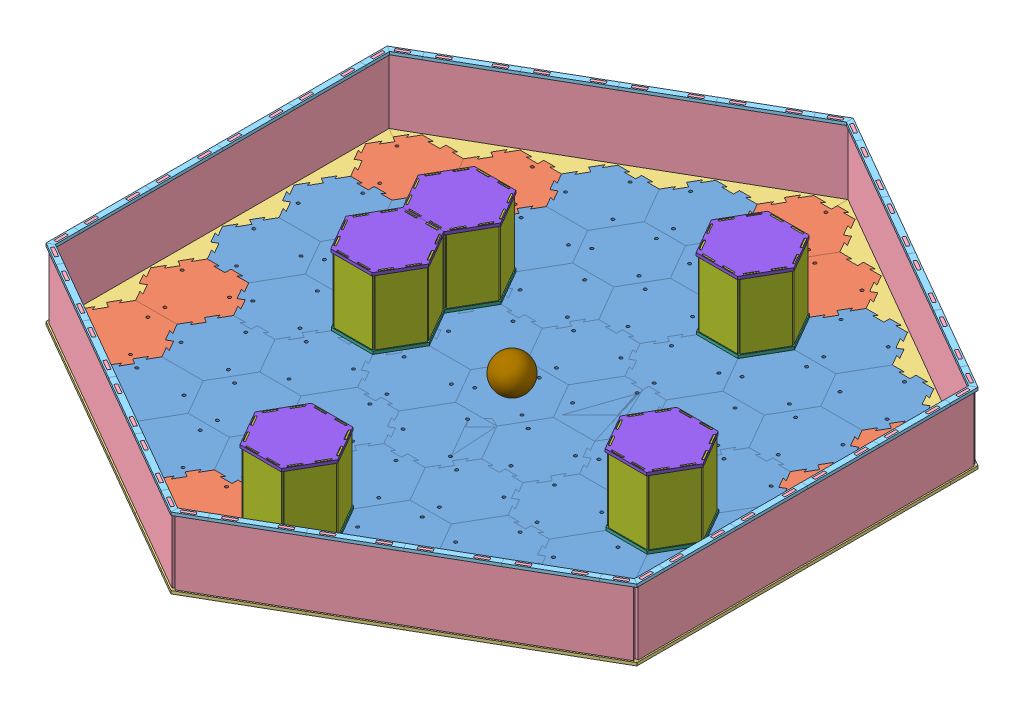
SolidWorks assembly examplepuzzle, configuration Default. Lengths in mm.
Overall size (1619.25 158.75 1704.77).
84 component instances, 9 part files, 90 mates.
Components (placement in the parent):
- module-1: module [Default] at origin size (444.5 6.35 474.64)
- module-2: module [Default] at (-400.05 0 -76.9897) size (444.5 6.35 474.64)
- module-3: module [Default] at (-266.7 0 307.9586) x (0.5 0 -0.866025) z (0.866025 0 0.5) size (444.5 6.35 474.64)
- module-5: module [Default] at (133.35 0 384.9483) x (-0.5 0 -0.866025) z (0.866025 0 -0.5) size (444.5 6.35 474.64)
- module-7: module [Default] at (400.05 0 76.9897) x (-1 0 0) z (0 0 -1) size (444.5 6.35 474.64)
- module-11: module [Default] at (266.7 0 -307.9586) size (444.5 6.35 474.64)
- module-12: module [Default] at (-133.35 0 -384.9483) size (444.5 6.35 474.64)
- module-13: module [Default] at origin size (444.5 6.35 474.64)
- module_2cell-1: module_2cell [Default] at (-133.35 0 538.9276) size (311.15 6.35 243.67)
- module_2cell-2: module_2cell [Default] at (400.05 0 384.9483) x (0.5 0 -0.866025) z (0.866025 0 0.5) size (311.15 6.35 243.67)
- module_2cell-4: module_2cell [Default] at (133.35 0 -538.9276) x (-1 0 0) z (0 0 -1) size (311.15 6.35 243.67)
- module_2cell-6: module_2cell [Default] at (-400.05 0 -384.9483) x (-0.5 0 0.866025) z (-0.866025 0 -0.5) size (311.15 6.35 243.67)
- module_2cell-9: module_2cell [Default] at (-533.4 0 153.9793) x (0.5 0 0.866025) z (-0.866025 0 0.5) size (311.15 6.35 243.67)
- module_2cell-11: module_2cell [Default] at (533.4 0 -153.9793) x (-0.5 0 -0.866025) z (0.866025 0 -0.5) size (311.15 6.35 243.67)
- Wall_seg_assembly-1: Wall_seg_assembly [Default] at (622.3 0 -230.969) x (0 0 1) z (-1 0 0) size (733.23 152.4 88.9)
  - border-1: border [Default] at origin size (733.23 6.35 88.9)
  - Wall_seg-1: Wall_seg [Default] at (230.969 69.85 -9.525) x (1 0 0) z (0 -1 0) size (721.64 6.35 152.4)
- Wall_seg_assembly-2: Wall_seg_assembly [Default] at (111.125 0 -654.4121) x (0.866025 0 0.5) z (-0.5 0 0.866025) size (733.23 152.4 88.9)
  - border-1: border [Default] at origin size (733.23 6.35 88.9)
  - Wall_seg-1: Wall_seg [Default] at (230.969 69.85 -9.525) x (1 0 0) z (0 -1 0) size (721.64 6.35 152.4)
- Wall_seg_assembly-4: Wall_seg_assembly [Default] at (-511.175 0 -423.4431) x (0.866025 0 -0.5) z (0.5 0 0.866025) size (733.23 152.4 88.9)
  - border-1: border [Default] at origin size (733.23 6.35 88.9)
  - Wall_seg-1: Wall_seg [Default] at (230.969 69.85 -9.525) x (1 0 0) z (0 -1 0) size (721.64 6.35 152.4)
- Wall_seg_assembly-6: Wall_seg_assembly [Default] at (-622.3 0 230.969) x (0 0 -1) z (1 0 0) size (733.23 152.4 88.9)
  - border-1: border [Default] at origin size (733.23 6.35 88.9)
  - Wall_seg-1: Wall_seg [Default] at (230.969 69.85 -9.525) x (1 0 0) z (0 -1 0) size (721.64 6.35 152.4)
- Wall_seg_assembly-8: Wall_seg_assembly [Default] at (-111.125 0 654.4121) x (-0.866025 0 -0.5) z (0.5 0 -0.866025) size (733.23 152.4 88.9)
  - border-1: border [Default] at origin size (733.23 6.35 88.9)
  - Wall_seg-1: Wall_seg [Default] at (230.969 69.85 -9.525) x (1 0 0) z (0 -1 0) size (721.64 6.35 152.4)
- Wall_seg_assembly-10: Wall_seg_assembly [Default] at (511.175 0 423.4431) x (-0.866025 0 0.5) z (-0.5 0 -0.866025) size (733.23 152.4 88.9)
  - border-1: border [Default] at origin size (733.23 6.35 88.9)
  - Wall_seg-1: Wall_seg [Default] at (230.969 69.85 -9.525) x (1 0 0) z (0 -1 0) size (721.64 6.35 152.4)
- wall_cover-1: wall_cover [Default] at (-511.175 146.05 -423.4431) x (0.866025 0 -0.5) z (0.5 0 0.866025) size (549.93 6.35 355.6)
- wall_cover-4: wall_cover [Default] at (111.125 146.05 -654.4121) x (0.866025 0 0.5) z (-0.5 0 0.866025) size (549.93 6.35 355.6)
- wall_cover-6: wall_cover [Default] at (622.3 146.05 -230.969) x (0 0 1) z (-1 0 0) size (549.93 6.35 355.6)
- wall_cover-8: wall_cover [Default] at (511.175 146.05 423.4431) x (-0.866025 0 0.5) z (-0.5 0 -0.866025) size (549.93 6.35 355.6)
- wall_cover-10: wall_cover [Default] at (-111.125 146.05 654.4121) x (-0.866025 0 -0.5) z (0.5 0 -0.866025) size (549.93 6.35 355.6)
- wall_cover-13: wall_cover [Default] at (-622.3 146.05 230.969) x (0 0 -1) z (1 0 0) size (549.93 6.35 355.6)
- obstacle_assemb-8: obstacle_assemb [Default] at (-266.7 0 0) x (0.5 0 -0.866025) z (0.866025 0 0.5) size (178.82 152.4 153.98)
  - obstacle_base-1: obstacle_base [Default] at origin size (177.8 6.35 153.98)
  - obstacle wall-1: obstacle wall [Default] at (-65.2792 76.2 -37.1024) x (0.5 0 -0.866025) z (0 -1 0) size (82.55 3.17 152.4)
  - obstacle wall-2: obstacle wall [Default] at (-64.7712 76.2 37.9823) x (-0.5 0 -0.866025) z (0 -1 0) size (82.55 3.17 152.4)
  - obstacle wall-4: obstacle wall [Default] at (0.508 76.2 75.0847) x (-1 0 0) z (0 -1 0) size (82.55 3.17 152.4)
  - obstacle wall-6: obstacle wall [Default] at (65.2792 76.2 37.1024) x (-0.5 0 0.866025) z (0 -1 0) size (82.55 3.17 152.4)
  - obstacle wall-8: obstacle wall [Default] at (64.7712 76.2 -37.9823) x (0.5 0 0.866025) z (0 -1 0) size (82.55 3.17 152.4)
  - obstacle wall-10: obstacle wall [Default] at (-0.508 76.2 -75.0847) x (1 0 0) z (0 -1 0) size (82.55 3.17 152.4)
  - obstacle_cover-1: obstacle_cover [Default] at (-1.016 146.05 0) size (177.8 6.35 153.98)
- obstacle_assemb-9: obstacle_assemb [Default] at (-266.7 0 -153.9793) x (-0.5 0 -0.866025) z (0.866025 0 -0.5) size (178.82 152.4 153.98)
  - obstacle_base-1: obstacle_base [Default] at origin size (177.8 6.35 153.98)
  - obstacle wall-1: obstacle wall [Default] at (-65.2792 76.2 -37.1024) x (0.5 0 -0.866025) z (0 -1 0) size (82.55 3.17 152.4)
  - obstacle wall-2: obstacle wall [Default] at (-64.7712 76.2 37.9823) x (-0.5 0 -0.866025) z (0 -1 0) size (82.55 3.17 152.4)
  - obstacle wall-4: obstacle wall [Default] at (0.508 76.2 75.0847) x (-1 0 0) z (0 -1 0) size (82.55 3.17 152.4)
  - obstacle wall-6: obstacle wall [Default] at (65.2792 76.2 37.1024) x (-0.5 0 0.866025) z (0 -1 0) size (82.55 3.17 152.4)
  - obstacle wall-8: obstacle wall [Default] at (64.7712 76.2 -37.9823) x (0.5 0 0.866025) z (0 -1 0) size (82.55 3.17 152.4)
  - obstacle wall-10: obstacle wall [Default] at (-0.508 76.2 -75.0847) x (1 0 0) z (0 -1 0) size (82.55 3.17 152.4)
  - obstacle_cover-1: obstacle_cover [Default] at (-1.016 146.05 0) size (177.8 6.35 153.98)
- obstacle_assemb-12: obstacle_assemb [Default] at (133.35 0 -384.9483) size (178.82 152.4 153.98)
  - obstacle_base-1: obstacle_base [Default] at origin size (177.8 6.35 153.98)
  - obstacle wall-1: obstacle wall [Default] at (-65.2792 76.2 -37.1024) x (0.5 0 -0.866025) z (0 -1 0) size (82.55 3.17 152.4)
  - obstacle wall-2: obstacle wall [Default] at (-64.7712 76.2 37.9823) x (-0.5 0 -0.866025) z (0 -1 0) size (82.55 3.17 152.4)
  - obstacle wall-4: obstacle wall [Default] at (0.508 76.2 75.0847) x (-1 0 0) z (0 -1 0) size (82.55 3.17 152.4)
  - obstacle wall-6: obstacle wall [Default] at (65.2792 76.2 37.1024) x (-0.5 0 0.866025) z (0 -1 0) size (82.55 3.17 152.4)
  - obstacle wall-8: obstacle wall [Default] at (64.7712 76.2 -37.9823) x (0.5 0 0.866025) z (0 -1 0) size (82.55 3.17 152.4)
  - obstacle wall-10: obstacle wall [Default] at (-0.508 76.2 -75.0847) x (1 0 0) z (0 -1 0) size (82.55 3.17 152.4)
  - obstacle_cover-1: obstacle_cover [Default] at (-1.016 146.05 0) size (177.8 6.35 153.98)
- obstacle_assemb-14: obstacle_assemb [Default] at (400.05 0 76.9897) x (0.5 0 -0.866025) z (0.866025 0 0.5) size (178.82 152.4 153.98)
  - obstacle_base-1: obstacle_base [Default] at origin size (177.8 6.35 153.98)
  - obstacle wall-1: obstacle wall [Default] at (-65.2792 76.2 -37.1024) x (0.5 0 -0.866025) z (0 -1 0) size (82.55 3.17 152.4)
  - obstacle wall-2: obstacle wall [Default] at (-64.7712 76.2 37.9823) x (-0.5 0 -0.866025) z (0 -1 0) size (82.55 3.17 152.4)
  - obstacle wall-4: obstacle wall [Default] at (0.508 76.2 75.0847) x (-1 0 0) z (0 -1 0) size (82.55 3.17 152.4)
  - obstacle wall-6: obstacle wall [Default] at (65.2792 76.2 37.1024) x (-0.5 0 0.866025) z (0 -1 0) size (82.55 3.17 152.4)
  - obstacle wall-8: obstacle wall [Default] at (64.7712 76.2 -37.9823) x (0.5 0 0.866025) z (0 -1 0) size (82.55 3.17 152.4)
  - obstacle wall-10: obstacle wall [Default] at (-0.508 76.2 -75.0847) x (1 0 0) z (0 -1 0) size (82.55 3.17 152.4)
  - obstacle_cover-1: obstacle_cover [Default] at (-1.016 146.05 0) size (177.8 6.35 153.98)
- obstacle_assemb-16: obstacle_assemb [Default] at (0 0 461.938) x (0.5 0 -0.866025) z (0.866025 0 0.5) size (178.82 152.4 153.98)
  - obstacle_base-1: obstacle_base [Default] at origin size (177.8 6.35 153.98)
  - obstacle wall-1: obstacle wall [Default] at (-65.2792 76.2 -37.1024) x (0.5 0 -0.866025) z (0 -1 0) size (82.55 3.17 152.4)
  - obstacle wall-2: obstacle wall [Default] at (-64.7712 76.2 37.9823) x (-0.5 0 -0.866025) z (0 -1 0) size (82.55 3.17 152.4)
  - obstacle wall-4: obstacle wall [Default] at (0.508 76.2 75.0847) x (-1 0 0) z (0 -1 0) size (82.55 3.17 152.4)
  - obstacle wall-6: obstacle wall [Default] at (65.2792 76.2 37.1024) x (-0.5 0 0.866025) z (0 -1 0) size (82.55 3.17 152.4)
  - obstacle wall-8: obstacle wall [Default] at (64.7712 76.2 -37.9823) x (0.5 0 0.866025) z (0 -1 0) size (82.55 3.17 152.4)
  - obstacle wall-10: obstacle wall [Default] at (-0.508 76.2 -75.0847) x (1 0 0) z (0 -1 0) size (82.55 3.17 152.4)
  - obstacle_cover-1: obstacle_cover [Default] at (-1.016 146.05 0) size (177.8 6.35 153.98)
- prey-1: prey [Default] at (0 38.1 0) size (76.2 76.2 76.2)
Mates (geometry in assembly coordinates):
- Coincident1: coincident anti-aligned: plane of module-1 through (-222.25 -6.35 76.9897) normal (-0.866025 0 -0.5); plane of module-2 through (-177.8 -6.35 0) normal (0.866025 0 0.5)
- Coincident2: coincident anti-aligned: plane of module-1 through (-177.8 -6.35 0) normal (-0.866025 0 0.5); plane of module-2 through (-222.25 -6.35 -76.9897) normal (0.866025 0 -0.5)
- Coincident3: coincident aligned: plane of module-1 through (-133.35 0 76.9897) normal (0 1 0); plane of module-2 through (-266.7 0 0) normal (0 1 0)
- Coincident4: coincident anti-aligned: plane of module-1 through (-44.45 -6.35 230.969) normal (-0.866025 0 0.5); plane of module-3 through (-88.9 -6.35 153.9793) normal (0.866025 0 -0.5)
- Coincident6: coincident anti-aligned: plane of module-1 through (-88.9 -6.35 153.9793) normal (0 0 1); plane of module-3 through (-177.8 -6.35 153.9793) normal (0 0 -1)
- Coincident7: coincident aligned: plane of module-1 through (0 0 153.9793) normal (0 1 0); plane of module-3 through (-133.35 0 230.969) normal (0 1 0)
- Coincident8: coincident anti-aligned: plane of module-1 through (177.8 -6.35 153.9793) normal (0 0 1); plane of module-5 through (88.9 -6.35 153.9793) normal (0 0 -1)
- Coincident9: coincident anti-aligned: plane of module-1 through (88.9 -6.35 153.9793) normal (0.866025 0 0.5); plane of module-5 through (44.45 -6.35 230.969) normal (-0.866025 0 -0.5)
- Coincident10: coincident aligned: plane of module-1 through (133.35 0 76.9897) normal (0 1 0); plane of module-5 through (133.35 0 230.969) normal (0 1 0)
- Coincident11: coincident anti-aligned: plane of module-1 through (222.25 -6.35 -76.9897) normal (0.866025 0 0.5); plane of module-7 through (177.8 -6.35 0) normal (-0.866025 0 -0.5)
- Coincident12: coincident anti-aligned: plane of module-1 through (177.8 -6.35 0) normal (0.866025 0 -0.5); plane of module-7 through (222.25 -6.35 76.9897) normal (-0.866025 0 0.5)
- Coincident13: coincident aligned: plane of module-1 through (133.35 0 -76.9897) normal (0 1 0); plane of module-7 through (266.7 0 0) normal (0 1 0)
- Coincident20: coincident anti-aligned: plane of module-1 through (177.8 -6.35 -153.9793) normal (0.866025 0 -0.5); plane of module-11 through (222.25 -6.35 -76.9897) normal (-0.866025 0 0.5)
- Coincident21: coincident anti-aligned: plane of module-7 through (222.25 -6.35 -76.9897) normal (0 0 -1); plane of module-11 through (311.15 -6.35 -76.9897) normal (0 0 1)
- Coincident22: coincident aligned: plane of module-1 through (133.35 0 -76.9897) normal (0 1 0); plane of module-11 through (266.7 0 -153.9793) normal (0 1 0)
- Coincident23: coincident anti-aligned: plane of module-2 through (-222.25 -6.35 -230.969) normal (0.866025 0 -0.5); plane of module-12 through (-177.8 -6.35 -153.9793) normal (-0.866025 0 0.5)
- Coincident24: coincident anti-aligned: plane of module-1 through (-177.8 -6.35 -153.9793) normal (0 0 -1); plane of module-12 through (-88.9 -6.35 -153.9793) normal (0 0 1)
- Coincident25: coincident aligned: plane of module-2 through (-266.7 0 -153.9793) normal (0 1 0); plane of module-12 through (-133.35 0 -230.969) normal (0 1 0)
- Coincident26: coincident anti-aligned: plane of module-3 through (-177.8 -6.35 461.938) normal (0.866025 0 0.5); plane of module_2cell-1 through (-177.8 -6.35 461.938) normal (-0.866025 0 -0.5)
- Coincident27: coincident anti-aligned: plane of module-3 through (-88.9 -6.35 461.938) normal (0 0 1); plane of module_2cell-1 through (-88.9 -6.35 461.938) normal (0 0 -1)
- Coincident28: coincident aligned: plane of module-3 through (-266.7 0 461.938) normal (0 1 0); plane of module_2cell-1 through (-133.35 0 538.9276) normal (0 1 0)
- Coincident29: coincident anti-aligned: plane of module-5 through (311.15 -6.35 384.9483) normal (0.866025 0 -0.5); plane of module_2cell-2 through (311.15 -6.35 384.9483) normal (-0.866025 0 0.5)
- Coincident30: coincident anti-aligned: plane of module-5 through (355.6 -6.35 307.9586) normal (0.866025 0 0.5); plane of module_2cell-2 through (355.6 -6.35 307.9586) normal (-0.866025 0 -0.5)
- Coincident31: coincident aligned: plane of module-5 through (266.7 0 307.9586) normal (0 1 0); plane of module_2cell-2 through (400.05 0 384.9483) normal (0 1 0)
- Coincident32: coincident anti-aligned: plane of module-11 through (177.8 -6.35 -461.938) normal (-0.866025 0 -0.5); plane of module_2cell-4 through (177.8 -6.35 -461.938) normal (0.866025 0 0.5)
- Coincident33: coincident anti-aligned: plane of module-11 through (88.9 -6.35 -461.938) normal (0 0 -1); plane of module_2cell-4 through (88.9 -6.35 -461.938) normal (0 0 1)
- Coincident34: coincident aligned: plane of module-11 through (266.7 0 -461.938) normal (0 1 0); plane of module_2cell-4 through (133.35 0 -538.9276) normal (0 1 0)
- Coincident35: coincident anti-aligned: plane of module-12 through (-311.15 -6.35 -384.9483) normal (-0.866025 0 0.5); plane of module_2cell-6 through (-311.15 -6.35 -384.9483) normal (0.866025 0 -0.5)
- Coincident36: coincident anti-aligned: plane of module-12 through (-355.6 -6.35 -307.9586) normal (-0.866025 0 -0.5); plane of module_2cell-6 through (-355.6 -6.35 -307.9586) normal (0.866025 0 0.5)
- Coincident37: coincident aligned: plane of module-12 through (-266.7 0 -461.938) normal (0 1 0); plane of module_2cell-6 through (-400.05 0 -384.9483) normal (0 1 0)
- Coincident41: coincident anti-aligned: plane of module-2 through (-488.95 -6.35 76.9897) normal (0 0 1); plane of module_2cell-9 through (-488.95 -6.35 76.9897) normal (0 0 -1)
- Coincident42: coincident anti-aligned: plane of module-2 through (-444.5 -6.35 153.9793) normal (-0.866025 0 0.5); plane of module_2cell-9 through (-444.5 -6.35 153.9793) normal (0.866025 0 -0.5)
- Coincident43: coincident aligned: plane of module-2 through (-400.05 0 76.9897) normal (0 1 0); plane of module_2cell-9 through (-533.4 0 153.9793) normal (0 1 0)
- Coincident44: coincident anti-aligned: plane of module-7 through (488.95 -6.35 -76.9897) normal (0 0 -1); plane of module_2cell-11 through (488.95 -6.35 -76.9897) normal (0 0 1)
- Coincident45: coincident anti-aligned: plane of module-7 through (444.5 -6.35 -153.9793) normal (0.866025 0 -0.5); plane of module_2cell-11 through (444.5 -6.35 -153.9793) normal (-0.866025 0 0.5)
- Coincident46: coincident aligned: plane of module-7 through (400.05 0 -76.9897) normal (0 1 0); plane of module_2cell-11 through (533.4 0 -153.9793) normal (0 1 0)
- Coincident56: coincident anti-aligned: plane of module_2cell-2 through (622.3 -6.35 307.9586) normal (0.866025 0 0.5); plane of Wall_seg_assembly-1/border-1 through (622.3 -6.35 307.9586) normal (-0.866025 0 -0.5)
- Coincident57: coincident anti-aligned: plane of module_2cell-2 through (577.85 -6.35 230.969) normal (0.866025 0 -0.5); plane of Wall_seg_assembly-1/border-1 through (577.85 -6.35 230.969) normal (-0.866025 0 0.5)
- Coincident58: coincident aligned: plane of module_2cell-2 through (533.4 0 307.9586) normal (0 1 0); plane of Wall_seg_assembly-1/border-1 through (622.3 0 230.969) normal (0 1 0)
- Coincident59: coincident anti-aligned: plane of module_2cell-11 through (577.85 -6.35 -384.9483) normal (0.866025 0 -0.5); plane of Wall_seg_assembly-2/border-1 through (577.85 -6.35 -384.9483) normal (-0.866025 0 0.5)
- Coincident60: coincident anti-aligned: plane of module_2cell-11 through (488.95 -6.35 -384.9483) normal (0 0 -1); plane of Wall_seg_assembly-2/border-1 through (488.95 -6.35 -384.9483) normal (0 0 1)
- Coincident61: coincident aligned: plane of module_2cell-11 through (533.4 0 -307.9586) normal (0 1 0); plane of Wall_seg_assembly-2/border-1 through (511.175 0 -423.4431) normal (0 1 0)
- Coincident62: coincident anti-aligned: plane of module_2cell-4 through (-44.45 -6.35 -692.9069) normal (0 0 -1); plane of Wall_seg_assembly-4/border-1 through (-44.45 -6.35 -692.9069) normal (0 0 1)
- Coincident63: coincident anti-aligned: plane of module_2cell-4 through (-88.9 -6.35 -615.9173) normal (-0.866025 0 -0.5); plane of Wall_seg_assembly-4/border-1 through (-88.9 -6.35 -615.9173) normal (0.866025 0 0.5)
- Coincident64: coincident aligned: plane of module_2cell-4 through (0 0 -615.9173) normal (0 1 0); plane of Wall_seg_assembly-4/border-1 through (-111.125 0 -654.4121) normal (0 1 0)
- Coincident65: coincident anti-aligned: plane of module_2cell-6 through (-622.3 -6.35 -307.9586) normal (-0.866025 0 -0.5); plane of Wall_seg_assembly-6/border-1 through (-622.3 -6.35 -307.9586) normal (0.866025 0 0.5)
- Coincident66: coincident anti-aligned: plane of module_2cell-6 through (-577.85 -6.35 -230.969) normal (-0.866025 0 0.5); plane of Wall_seg_assembly-6/border-1 through (-577.85 -6.35 -230.969) normal (0.866025 0 -0.5)
- Coincident67: coincident aligned: plane of module_2cell-6 through (-533.4 0 -307.9586) normal (0 1 0); plane of Wall_seg_assembly-6/border-1 through (-622.3 0 -230.969) normal (0 1 0)
- Coincident68: coincident anti-aligned: plane of module_2cell-9 through (-577.85 -6.35 384.9483) normal (-0.866025 0 0.5); plane of Wall_seg_assembly-8/border-1 through (-577.85 -6.35 384.9483) normal (0.866025 0 -0.5)
- Coincident69: coincident anti-aligned: plane of module_2cell-9 through (-488.95 -6.35 384.9483) normal (0 0 1); plane of Wall_seg_assembly-8/border-1 through (-488.95 -6.35 384.9483) normal (0 0 -1)
- Coincident70: coincident aligned: plane of module_2cell-9 through (-533.4 0 307.9586) normal (0 1 0); plane of Wall_seg_assembly-8/border-1 through (-511.175 0 423.4431) normal (0 1 0)
- Coincident71: coincident anti-aligned: plane of module_2cell-1 through (44.45 -6.35 692.9069) normal (0 0 1); plane of Wall_seg_assembly-10/border-1 through (44.45 -6.35 692.9069) normal (0 0 -1)
- Coincident72: coincident anti-aligned: plane of module_2cell-1 through (88.9 -6.35 615.9173) normal (0.866025 0 0.5); plane of Wall_seg_assembly-10/border-1 through (88.9 -6.35 615.9173) normal (-0.866025 0 -0.5)
- Coincident73: coincident aligned: plane of module_2cell-1 through (0 0 615.9173) normal (0 1 0); plane of Wall_seg_assembly-10/border-1 through (111.125 0 654.4121) normal (0 1 0)
- Coincident79: coincident anti-aligned: plane of Wall_seg_assembly-4/Wall_seg-1 through (-599.7941 139.7 -383.2774) normal (0.866025 0 -0.5); plane of wall_cover-1 through (-599.7941 139.7 -383.2774) normal (-0.866025 0 0.5)
- Coincident80: coincident anti-aligned: plane of Wall_seg_assembly-4/Wall_seg-1 through (-315.9125 69.85 -547.1765) normal (-0.5 0 -0.866025); plane of wall_cover-1 through (-621.7912 139.7 -370.5774) normal (0.5 0 0.866025)
- Coincident81: coincident aligned: plane of Wall_seg_assembly-4/Wall_seg-1 through (-625.2153 146.05 -361.2681) normal (0 1 0); plane of wall_cover-1 through (-644.525 146.05 -346.4535) normal (0 1 0)
- Coincident88: coincident anti-aligned: plane of Wall_seg_assembly-2/Wall_seg-1 through (32.0309 139.7 -711.0756) normal (0.866025 0 0.5); plane of wall_cover-4 through (32.0309 139.7 -711.0756) normal (-0.866025 0 -0.5)
- Coincident89: coincident anti-aligned: plane of Wall_seg_assembly-2/Wall_seg-1 through (315.9125 69.85 -547.1765) normal (0.5 0 -0.866025); plane of wall_cover-4 through (10.0338 139.7 -723.7756) normal (-0.5 0 0.866025)
- Coincident90: coincident aligned: plane of Wall_seg_assembly-2/Wall_seg-1 through (0.2597 146.05 -722.0864) normal (0 1 0); plane of wall_cover-4 through (-22.225 146.05 -731.4018) normal (0 1 0)
- Coincident91: coincident anti-aligned: plane of Wall_seg_assembly-1/Wall_seg-1 through (631.825 139.7 -327.7983) normal (0 0 1); plane of wall_cover-6 through (631.825 139.7 -327.7983) normal (0 0 -1)
- Coincident92: coincident anti-aligned: plane of Wall_seg_assembly-1/Wall_seg-1 through (631.825 69.85 0) normal (1 0 0); plane of wall_cover-6 through (631.825 139.7 -353.1983) normal (-1 0 0)
- Coincident93: coincident aligned: plane of Wall_seg_assembly-1/Wall_seg-1 through (625.475 146.05 -360.8183) normal (0 1 0); plane of wall_cover-6 through (622.3 146.05 -384.9483) normal (0 1 0)
- Coincident94: coincident anti-aligned: plane of Wall_seg_assembly-10/Wall_seg-1 through (599.7941 139.7 383.2774) normal (-0.866025 0 0.5); plane of wall_cover-8 through (599.7941 139.7 383.2774) normal (0.866025 0 -0.5)
- Coincident95: coincident anti-aligned: plane of Wall_seg_assembly-10/Wall_seg-1 through (315.9125 69.85 547.1765) normal (0.5 0 0.866025); plane of wall_cover-8 through (621.7912 139.7 370.5774) normal (-0.5 0 -0.866025)
- Coincident96: coincident aligned: plane of Wall_seg_assembly-10/Wall_seg-1 through (625.2153 146.05 361.2681) normal (0 1 0); plane of wall_cover-8 through (644.525 146.05 346.4535) normal (0 1 0)
- Coincident97: coincident anti-aligned: plane of Wall_seg_assembly-8/Wall_seg-1 through (-32.0309 139.7 711.0756) normal (-0.866025 0 -0.5); plane of wall_cover-10 through (-32.0309 139.7 711.0756) normal (0.866025 0 0.5)
- Coincident98: coincident anti-aligned: plane of Wall_seg_assembly-8/Wall_seg-1 through (-315.9125 69.85 547.1765) normal (-0.5 0 0.866025); plane of wall_cover-10 through (-10.0338 139.7 723.7756) normal (0.5 0 -0.866025)
- Coincident99: coincident aligned: plane of Wall_seg_assembly-8/Wall_seg-1 through (-0.2597 146.05 722.0864) normal (0 1 0); plane of wall_cover-10 through (22.225 146.05 731.4018) normal (0 1 0)
- Coincident103: coincident anti-aligned: plane of Wall_seg_assembly-6/Wall_seg-1 through (-631.825 139.7 327.7983) normal (0 0 -1); plane of wall_cover-13 through (-631.825 139.7 327.7983) normal (0 0 1)
- Coincident104: coincident anti-aligned: plane of Wall_seg_assembly-6/Wall_seg-1 through (-631.825 69.85 0) normal (-1 0 0); plane of wall_cover-13 through (-631.825 139.7 353.1983) normal (1 0 0)
- Coincident105: coincident aligned: plane of Wall_seg_assembly-6/Wall_seg-1 through (-625.475 146.05 360.8183) normal (0 1 0); plane of wall_cover-13 through (-622.3 146.05 384.9483) normal (0 1 0)
- Concentric6: concentric aligned: cylinder of module-2 through (-266.7 -6.35 58.6588) axis (0 1 0) radius 3.175; cylinder of obstacle_assemb-8/obstacle_base-1 through (-266.7 0 58.6588) axis (0 1 0) radius 3.0734
- Concentric7: concentric aligned: cylinder of module-2 through (-215.9 -6.35 -29.3294) axis (0 1 0) radius 3.175; cylinder of obstacle_assemb-8/obstacle_base-1 through (-215.9 0 -29.3294) axis (0 1 0) radius 3.0734
- Coincident119: coincident anti-aligned: plane of module-2 through (-266.7 0 0) normal (0 1 0); plane of obstacle_assemb-8/obstacle_base-1 through (-266.7 0 0) normal (0 -1 0)
- Concentric8: concentric aligned: cylinder of module-2 through (-215.9 -6.35 -124.6499) axis (0 1 0) radius 3.175; cylinder of obstacle_assemb-9/obstacle_base-1 through (-215.9 0 -124.6499) axis (0 1 0) radius 3.0734
- Concentric9: concentric aligned: cylinder of module-2 through (-266.7 -6.35 -212.6381) axis (0 1 0) radius 3.175; cylinder of obstacle_assemb-9/obstacle_base-1 through (-266.7 0 -212.6381) axis (0 1 0) radius 3.0734
- Coincident120: coincident anti-aligned: plane of module-2 through (-266.7 0 -153.9793) normal (0 1 0); plane of obstacle_assemb-9/obstacle_base-1 through (-266.7 0 -153.9793) normal (0 -1 0)
- Concentric12: concentric aligned: cylinder of module-11 through (82.55 -6.35 -355.6189) axis (0 1 0) radius 3.175; cylinder of obstacle_assemb-12/obstacle_base-1 through (82.55 0 -355.6189) axis (0 1 0) radius 3.0734
- Concentric13: concentric aligned: cylinder of module-11 through (184.15 -6.35 -355.6189) axis (0 1 0) radius 3.175; cylinder of obstacle_assemb-12/obstacle_base-1 through (184.15 0 -355.6189) axis (0 1 0) radius 3.0734
- Coincident122: coincident anti-aligned: plane of module-11 through (133.35 0 -384.9483) normal (0 1 0); plane of obstacle_assemb-12/obstacle_base-1 through (133.35 0 -384.9483) normal (0 -1 0)
- Concentric14: concentric aligned: cylinder of module-7 through (400.05 -6.35 135.6484) axis (0 1 0) radius 3.175; cylinder of obstacle_assemb-14/obstacle_base-1 through (400.05 0 135.6484) axis (0 1 0) radius 3.0734
- Concentric15: concentric aligned: cylinder of module-7 through (450.85 -6.35 47.6603) axis (0 1 0) radius 3.175; cylinder of obstacle_assemb-14/obstacle_base-1 through (450.85 0 47.6603) axis (0 1 0) radius 3.0734
- Coincident123: coincident anti-aligned: plane of module-7 through (400.05 0 76.9897) normal (0 1 0); plane of obstacle_assemb-14/obstacle_base-1 through (400.05 0 76.9897) normal (0 -1 0)
- Concentric16: concentric aligned: cylinder of module-5 through (0 -6.35 520.5967) axis (0 1 0) radius 3.175; cylinder of obstacle_assemb-16/obstacle_base-1 through (0 0 520.5967) axis (0 1 0) radius 3.0734
- Concentric17: concentric aligned: cylinder of module-5 through (50.8 -6.35 432.6086) axis (0 1 0) radius 3.175; cylinder of obstacle_assemb-16/obstacle_base-1 through (50.8 0 432.6086) axis (0 1 0) radius 3.0734
- Coincident124: coincident anti-aligned: plane of module-5 through (0 0 461.938) normal (0 1 0); plane of obstacle_assemb-16/obstacle_base-1 through (0 0 461.938) normal (0 -1 0)
- Tangent1: tangent anti-aligned: plane of module-13 through (0 0 0) normal (0 1 0); sphere of prey-1
- Coincident126: coincident aligned: plane of prey-1 through (0 38.1 0) normal (0 0 1); plane of assembly
- Coincident125: coincident aligned: plane of ? through (0 38.1 0.9043) normal (1 0 0)
